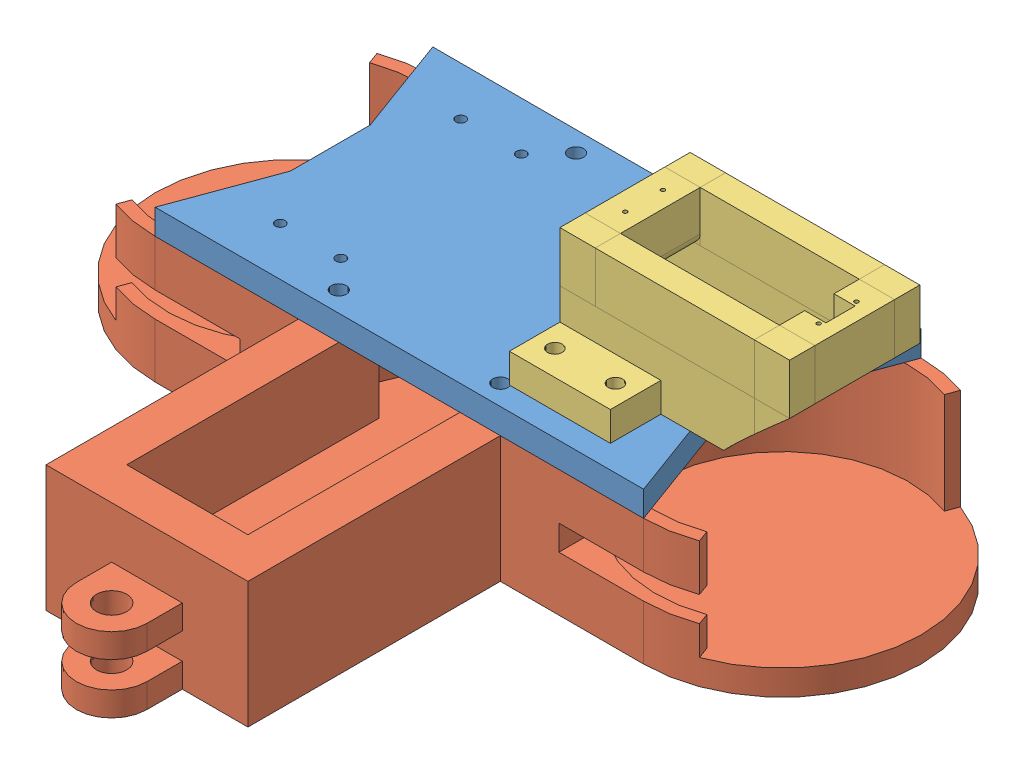
SolidWorks assembly Hip and servo mount assem v2, configuration Default. Lengths in mm.
Overall size (192.74 66.06 151.13).
3 component instances, 3 part files, 6 mates.
Components (placement in the parent):
- servo mount plate hips V2-1: servo mount plate hips V2 [Default] at (-38.2866 61.8732 0.3708) size (122.89 6.35 69.85)
- hip joint v2-2: hip joint v2 [Default] at (24.2446 36.4732 -20.8547) size (192.74 31.75 151.13)
- servomount v1-1: servomount v1 [Default] at (11.3954 36.9812 -34.5272) size (57.78 27.96 58.16)
Mates (geometry in assembly coordinates):
- Coincident8: coincident anti-aligned: plane of servo mount plate hips V2-1 through (-38.2866 61.8732 0.3708) normal (0 -1 0); plane of hip joint v2-2 through (24.2446 61.8732 -20.8547) normal (0 1 0)
- Coincident9: coincident aligned: plane of servo mount plate hips V2-1 through (-38.2866 68.2232 0.3708) normal (0 0 1); plane of hip joint v2-2 through (24.2446 61.8732 0.3708) normal (0 0 1)
- Coincident10: coincident aligned: line of servo mount plate hips V2-1 through (-38.2866 68.2232 0.3708) axis (0 -1 0); line of hip joint v2-2 through (-38.2866 61.8732 0.3708) axis (0 -1 0)
- Coincident11: coincident anti-aligned: plane of servo mount plate hips V2-1 through (-38.2866 68.2232 0.3708) normal (0 1 0); plane of servomount v1-1 through (45.0291 68.2232 36.3122) normal (0 -1 0)
- Concentric1: concentric anti-aligned: circle of servomount v1-1; circle of servo mount plate hips V2-1
- Parallel1: parallel aligned: plane of servo mount plate hips V2-1 through (-38.2866 68.2232 0.3708) normal (0 0 1); plane of servomount v1-1 through (11.3954 36.9812 -5.4472) normal (0 0 1)
